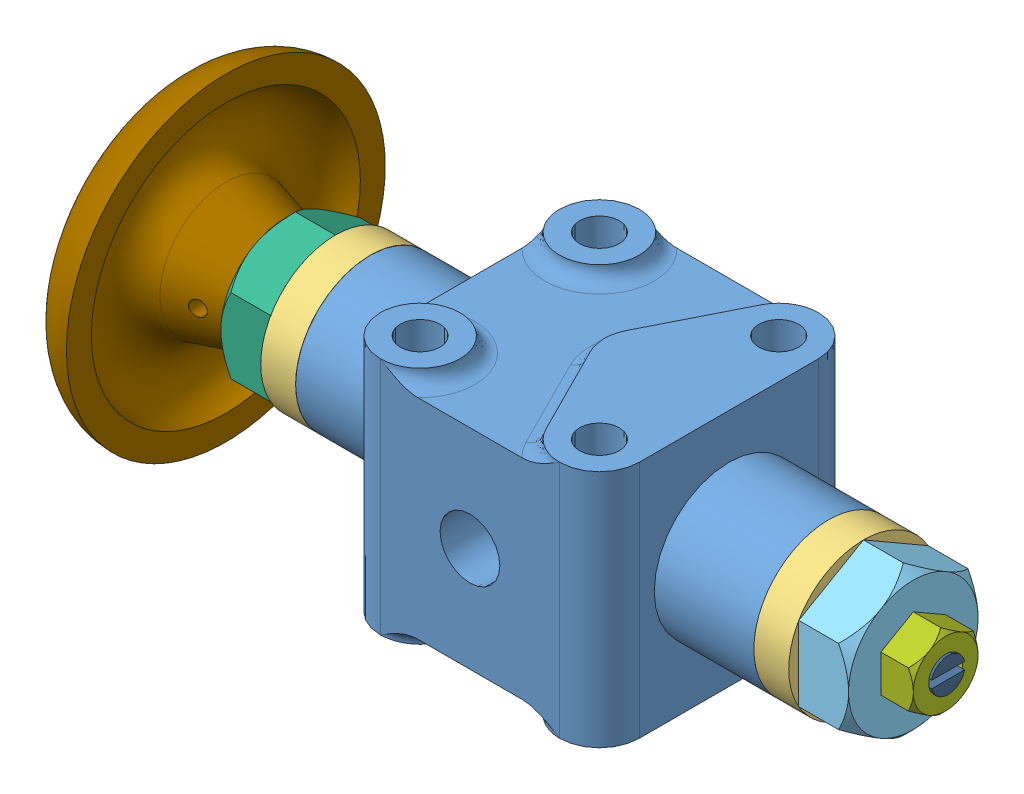
SolidWorks assembly asseblyincomplete, configuration Default. Lengths in mm.
Overall size (155 64 64).
11 component instances, 10 part files, 28 mates.
Components (placement in the parent):
- valve1-1: valve1 [Default] at (28.9129 61.4679 64.3396) size (92 49.87 52)
- valve10-1: valve10 [Default] at (-0.1589 61.4679 64.3396) x (1 0 0) z (0 0.381849 0.924225) size (30 10 10)
- valve12-1: valve12 [Default] at (-24.0871 61.4679 64.3396) x (0 -0.787052 0.616886) z (0 0.616886 0.787052) size (30 7 30)
- valve5-1: valve5 [Default] at (41.8411 61.4679 64.3396) x (0 -1 0) z (0 0 1) size (14 36 14)
- valve6-1: valve6 [Default] at (81.9129 61.4679 64.3396) x (0 -0.866025 0.5) z (0 0.5 0.866025) size (25.98 27.51 30)
- valve7-1: valve7 [Default] at (-24.0871 61.4679 64.3396) x (0 0 -1) z (0 1 0) size (25.98 22.01 30)
- valve8-1: valve8 [Default] at (91.9129 61.4679 64.3396) x (0 -1 0) z (0 0 1) size (15 6.5 12.99)
- valve12-2: valve12 [Default] at (81.9129 61.4679 64.3396) x (0 -0.033345 -0.999444) z (0 0.999444 -0.033345) size (30 7 30)
- Part26-1: Part26 [Default] at (-45.1589 61.4679 64.3396) x (-1 0 0) z (0 0 -1) size (45 6.8 6.8)
- valve2-1: valve2 [Default] at (-34.0871 61.4679 64.3396) x (0 1 0) z (0 0 1) size (64 22 64)
- valve11-2: valve11 [Default] at (76.9129 61.4679 64.3396) size (53 6.8 6.8)
Mates (geometry in assembly coordinates):
- Concentric2: concentric aligned: cylinder of valve1-1 through (74.9139 61.4679 64.3396) axis (-1 0 0) radius 3; cylinder of valve5-1 through (55.8411 61.4679 64.3396) axis (-1 0 0) radius 7
- Coincident2: coincident: circle of valve1-1; cone of valve5-1 through (41.8411 61.4679 64.3396) axis (-1 0 0)
- Concentric3: concentric anti-aligned: cylinder of valve10-1 through (21.8411 61.4679 64.3396) axis (1 0 0) radius 1.5; cone of valve5-1 through (30.8411 61.4679 64.3396) axis (-1 0 0)
- Coincident3: coincident anti-aligned: plane of valve10-1 through (29.8411 61.4679 64.3396) normal (1 0 0); plane of valve5-1 through (29.8411 61.4679 64.3396) normal (-1 0 0)
- Parallel1: parallel anti-aligned: plane of valve1-1 through (-17.0871 61.4679 64.3396) normal (-1 0 0); plane of valve12-1 through (-17.0871 61.4679 64.3396) normal (1 0 0)
- Concentric9: concentric aligned: cylinder of valve1-1 through (-1.0871 61.4679 64.3396) axis (-1 0 0) radius 10; cylinder of valve12-1 through (-17.0871 61.4679 64.3396) axis (-1 0 0) radius 10
- Coincident6: coincident anti-aligned: plane of valve1-1 through (-17.0871 61.4679 64.3396) normal (-1 0 0); plane of valve12-1 through (-17.0871 61.4679 64.3396) normal (1 0 0)
- Parallel2: parallel anti-aligned: plane of valve1-1 through (74.9129 61.4679 64.3396) normal (1 0 0); plane of valve12-2 through (74.9129 61.4679 64.3396) normal (-1 0 0)
- Concentric10: concentric aligned: cylinder of valve1-1 through (60.9129 61.4679 64.3396) axis (1 0 0) radius 10; cylinder of valve12-2 through (74.9129 61.4679 64.3396) axis (1 0 0) radius 10
- Coincident7: coincident anti-aligned: plane of valve1-1 through (74.9129 61.4679 64.3396) normal (1 0 0); plane of valve12-2 through (74.9129 61.4679 64.3396) normal (-1 0 0)
- Concentric12: concentric anti-aligned: circle of valve10-1; cylinder of Part26-1 through (-6.6589 61.4679 64.3396) axis (-1 0 0) radius 3.4
- Angle1: planar angle = 1.570796 rad aligned: cylinder of valve1-1 through (10.9129 36.532 46.3396) axis (0 1 0) radius 4; cylinder of Part26-1 through (-39.1589 61.4679 70.3396) axis (0 0 -1) radius 1.5
- Coincident8: coincident anti-aligned: plane of valve10-1 through (-0.1589 61.4679 64.3396) normal (-1 0 0); plane of Part26-1 through (-0.1589 61.4679 64.3396) normal (1 0 0)
- Concentric13: concentric aligned: cylinder of valve12-1 through (-17.0871 61.4679 64.3396) axis (-1 0 0) radius 10; cylinder of valve7-1 through (-12.0871 61.4679 64.3396) axis (-1 0 0) radius 10
- Perpendicular1: perpendicular: plane of valve1-1 through (28.9129 82.4679 64.3396) normal (0 1 0); plane of valve7-1 through (-34.0871 53.9679 77.33) normal (0 0 1)
- Coincident9: coincident anti-aligned: plane of valve12-1 through (-24.0871 61.4679 64.3396) normal (-1 0 0); plane of valve7-1 through (-24.0871 61.4679 64.3396) normal (1 0 0)
- Parallel3: parallel aligned: plane of valve7-1 through (-34.0871 61.4679 64.3396) normal (-1 0 0); plane of valve2-1 through (-56.0871 61.4679 64.3396) normal (-1 0 0)
- Concentric14: concentric anti-aligned: cylinder of Part26-1 through (-6.6589 61.4679 64.3396) axis (-1 0 0) radius 3.4; cylinder of valve2-1 through (-34.0871 61.4679 64.3396) axis (1 0 0) radius 3.4
- Coincident10: coincident anti-aligned: plane of valve7-1 through (-34.0871 61.4679 64.3396) normal (-1 0 0); plane of valve2-1 through (-34.0871 61.4679 64.3396) normal (1 0 0)
- Concentric16: concentric aligned: cylinder of valve6-1 through (64.4129 61.4679 64.3396) axis (1 0 0) radius 10; cylinder of valve12-2 through (74.9129 61.4679 64.3396) axis (1 0 0) radius 10
- Perpendicular3: perpendicular: plane of valve1-1 through (46.9129 85.4679 46.3396) normal (0 1 0); plane of valve6-1 through (91.9129 68.9679 77.33) normal (0 0 1)
- Coincident11: coincident anti-aligned: plane of valve6-1 through (81.9129 61.4679 64.3396) normal (-1 0 0); plane of valve12-2 through (81.9129 61.4679 64.3396) normal (1 0 0)
- Concentric18: concentric aligned: cylinder of valve6-1 through (91.9129 61.4679 64.3396) axis (1 0 0) radius 3.4; cylinder of valve11-2 through (46.9129 61.4679 64.3396) axis (1 0 0) radius 2.5
- Parallel6: parallel aligned: plane of valve1-1 through (46.9129 37.4679 46.3396) normal (0 -1 0); plane of valve11-2 through (94.9129 62.2179 59.3396) normal (0 -1 0)
- Distance1: distance = 7 mm aligned: plane of valve6-1 through (91.9129 61.4679 64.3396) normal (1 0 0); plane of valve11-2 through (98.9129 61.4679 64.3396) normal (1 0 0)
- Concentric19: concentric anti-aligned: cylinder of valve8-1 through (98.4129 61.4679 64.3396) axis (1 0 0) radius 3.4; cylinder of valve11-2 through (98.9129 61.4679 64.3396) axis (-1 0 0) radius 3.4
- Perpendicular4: perpendicular: plane of valve1-1 through (46.9129 85.4679 46.3396) normal (0 1 0); plane of valve8-1 through (98.4129 65.2179 70.8348) normal (0 0 1)
- Coincident13: coincident anti-aligned: plane of valve6-1 through (91.9129 61.4679 64.3396) normal (1 0 0); plane of valve8-1 through (91.9129 61.4679 64.3396) normal (-1 0 0)
